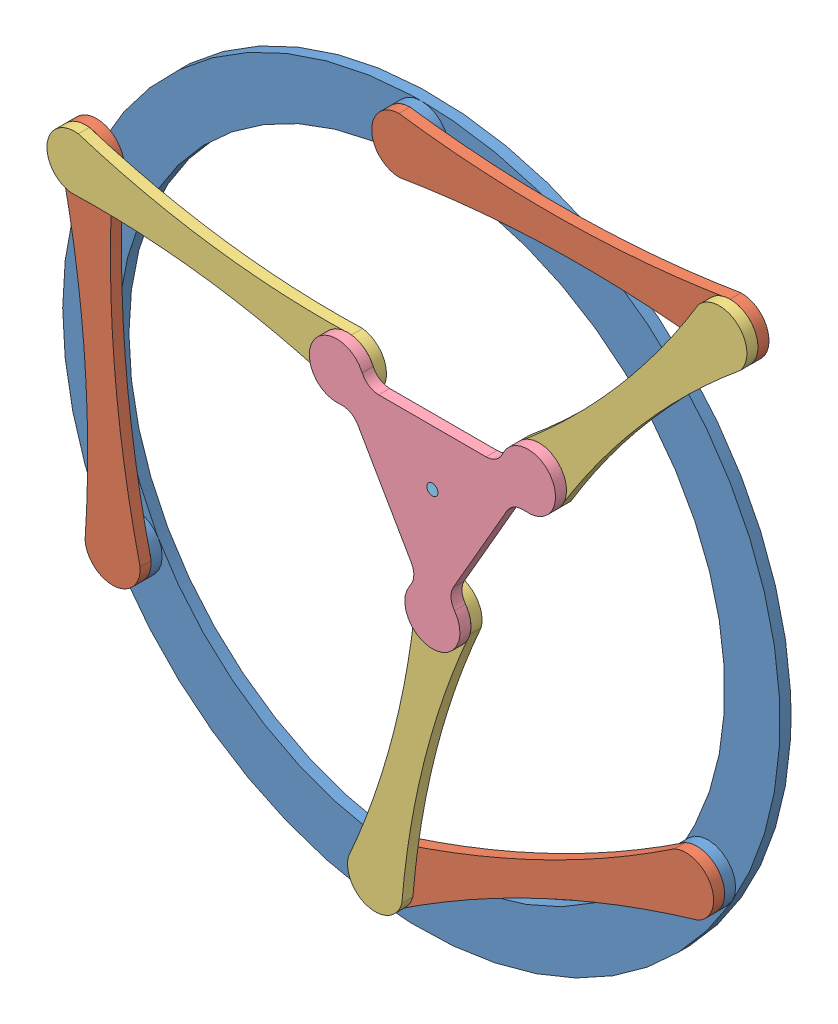
SolidWorks assembly 3RRR - Elbow Up, configuration Default. Lengths in mm.
Overall size (660.23 664.5 50).
9 component instances, 5 part files, 21 mates.
Components (placement in the parent):
- Base-1: Base [Default] at origin size (650 650 20)
- Proximal Link-1: Proximal Link [Default] at (-272.0437 -0.4999 20) x (-0.081574 0.996667 0) z (0 0 1) size (350 50 20)
- Proximal Link-2: Proximal Link [Default] at (123.963 -213.6101 20) x (-0.905631 -0.424068 0) z (0 0 1) size (350 50 20)
- Proximal Link-3: Proximal Link [Default] at (149.985 302.119 20) x (0.9999 0.014127 0) z (0 0 1) size (350 50 20)
- Distal Link-1: Distal Link [Default] at (-160.4411 132.0001 30) x (0.990709 -0.136001 0) z (0 0 1) size (300 50 20)
- Distal Link-2: Distal Link [Default] at (19.0592 -156.1101 30) x (0.247526 0.968881 0) z (0 0 1) size (300 50 20)
- Distal Link-3: Distal Link [Default] at (218.2863 209.619 30) x (-0.65347 -0.756952 0) z (0 0 1) size (300 50 20)
- Platform-1: Platform [Default] at (50 65 50) x (-1 0 0) z (0 0 1) size (223.21 200 20)
- Pen-1: Pen [Default] at (50 65 50) x (0.104755 0.994498 0) z (0 0 -1) size (10 10 50)
Mates (geometry in assembly coordinates):
- Coincident5: coordinate: unknown of Base-1
- Concentric1: concentric anti-aligned: cylinder of Base-1 through (-259.8076 -150 20) axis (0 0 -1) radius 16.25; cylinder of Proximal Link-1 through (-259.8076 -150 10) axis (0 0 1) radius 16.25
- Coincident6: coincident anti-aligned: plane of Base-1 through (0 0 10) normal (0 0 1); plane of Proximal Link-1 through (-259.8076 -150 10) normal (0 0 -1)
- Concentric2: concentric anti-aligned: cylinder of Base-1 through (259.8076 -150 20) axis (0 0 -1) radius 16.25; cylinder of Proximal Link-2 through (259.8076 -150 10) axis (0 0 1) radius 16.25
- Coincident7: coincident anti-aligned: plane of Base-1 through (0 0 10) normal (0 0 1); plane of Proximal Link-2 through (259.8076 -150 10) normal (0 0 -1)
- Concentric3: concentric anti-aligned: cylinder of Base-1 through (0 300 20) axis (0 0 -1) radius 16.25; cylinder of Proximal Link-3 through (0 300 10) axis (0 0 1) radius 16.25
- Coincident8: coincident anti-aligned: plane of Base-1 through (0 0 10) normal (0 0 1); plane of Proximal Link-3 through (0 300 10) normal (0 0 -1)
- Concentric4: concentric aligned: cylinder of Proximal Link-1 through (-284.2797 149.0002 20) axis (0 0 1) radius 16.25; cylinder of Distal Link-1 through (-284.2797 149.0002 20) axis (0 0 1) radius 16.25
- Coincident9: coincident anti-aligned: plane of Proximal Link-1 through (-783.3155 32.9051 30) normal (0 0 1); plane of Distal Link-1 through (-46.5349 502.2034 30) normal (0 0 -1)
- Concentric5: concentric aligned: cylinder of Proximal Link-2 through (-11.8816 -277.2203 20) axis (0 0 1) radius 16.25; cylinder of Distal Link-2 through (-11.8816 -277.2203 20) axis (0 0 1) radius 16.25
- Coincident10: coincident anti-aligned: plane of Proximal Link-2 through (270.9764 -704.4277 30) normal (0 0 1); plane of Distal Link-2 through (-335.8301 -0.9369 30) normal (0 0 -1)
- Concentric6: concentric aligned: cylinder of Proximal Link-3 through (299.9701 304.238 20) axis (0 0 1) radius 16.25; cylinder of Distal Link-3 through (299.9701 304.238 20) axis (0 0 1) radius 16.25
- Coincident11: coincident anti-aligned: plane of Proximal Link-3 through (217.8175 809.9709 30) normal (0 0 1); plane of Distal Link-3 through (466.7931 -87.4828 30) normal (0 0 -1)
- Concentric8: concentric aligned: cylinder of Distal Link-1 through (-36.6025 115 30) axis (0 0 1) radius 16.25; cylinder of Platform-1 through (-36.6025 115 30) axis (0 0 1) radius 16.25
- Coincident12: coincident anti-aligned: plane of Distal Link-1 through (-46.5349 502.2034 40) normal (0 0 1); plane of Platform-1 through (16.9699 -10.2901 40) normal (0 0 -1)
- Concentric9: concentric aligned: cylinder of Distal Link-2 through (50 -34.9999 30) axis (0 0 1) radius 16.25; cylinder of Platform-1 through (50 -34.9999 30) axis (0 0 1) radius 16.25
- Concentric10: concentric aligned: cylinder of Distal Link-3 through (136.6025 115 30) axis (0 0 1) radius 16.25; cylinder of Platform-1 through (136.6025 115 30) axis (0 0 1) radius 16.25
- Distance2: distance = 115 mm aligned: plane of Platform-1 through (1.3118 115 40) normal (0 1 0)
- Distance1: distance = 96.0469 mm: point of assembly; point of assembly; point of Platform-1
- Coincident13: coincident aligned: plane of Platform-1 through (16.9699 -10.2901 50) normal (0 0 1); plane of Pen-1 through (50 65 50) normal (0 0 1)
- Concentric11: concentric aligned: cylinder of Platform-1 through (50 65 40) axis (0 0 1) radius 5; cylinder of Pen-1 through (50 65 10) axis (0 0 1) radius 5
